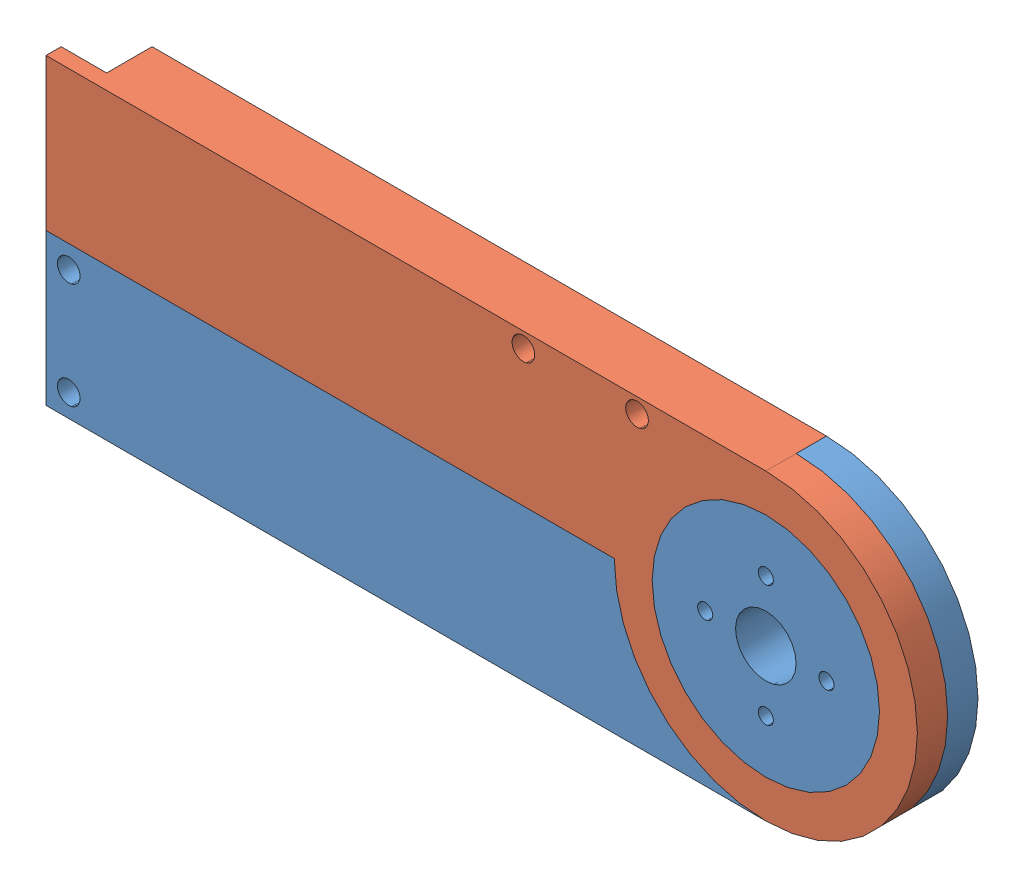
SolidWorks assembly barre haute, configuration Défaut. Lengths in mm.
Overall size (115 40 8).
2 component instances, 2 part files, 3 mates.
Components (placement in the parent):
- alpha-1: alpha [Défaut] at (-26.0152 -29.6431 98.575) size (115 40 8)
- beta bis-1: beta bis [Défaut] at (-36.2344 -5.3302 106.575) x (-1 0 0) z (0 0 -1) size (115 40 8)
Mates (geometry in assembly coordinates):
- Coïncidente1: coincident: plane of alpha-1 through (6.977 -1.5438 102.575) normal (0 0 1); plane of beta bis-1 through (6.977 -1.5438 102.575) normal (0 0 -1)
- Coaxiale1: concentric: cylinder of alpha-1 through (6.977 -1.5438 102.575) axis (0 0 1) radius 15; cylinder of beta bis-1 through (6.977 -1.5438 98.575) axis (0 0 1) radius 15
- Angle1: planar angle = 0 rad anti-aligned: plane of alpha-1 through (-26.0152 -21.5438 106.575) normal (0 -1 0); plane of beta bis-1 through (-36.2344 18.4562 98.575) normal (0 1 0)
